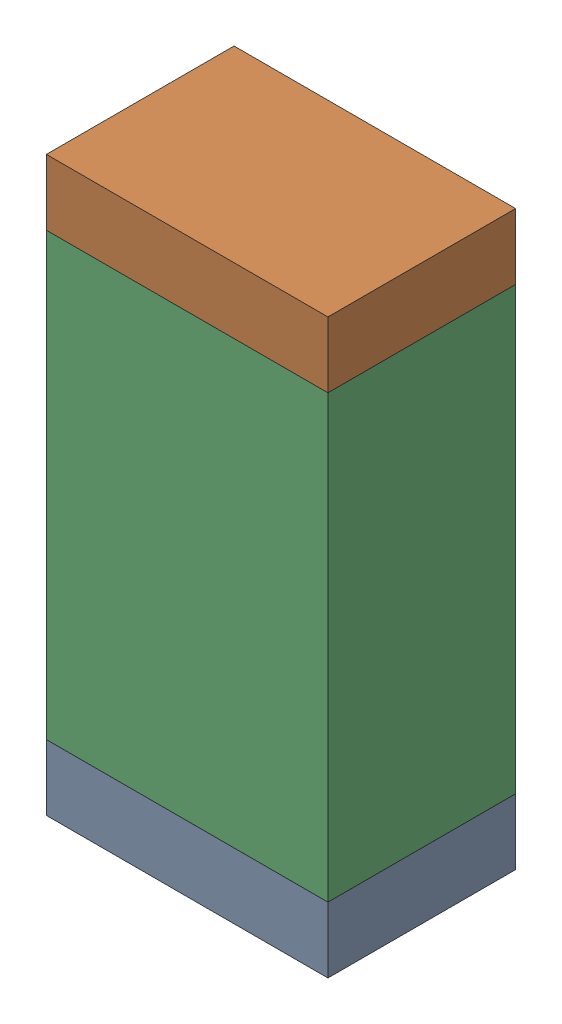
SolidWorks assembly C3, configuration Default. Lengths in mm.
Overall size (0.76 1.55 0.51).
6 component instances, 2 part files, 0 mates.
Components (placement in the parent):
- 822501776-1: 822501776 [Default] at (28.447 8.0951 0) size (0.76 0.18 0.51)
  - Extruded_3-1: Extruded_3 [Default] at origin size (0.76 0.18 0.51)
- 822501776-2: 822501776 [Default] at (28.447 9.4667 0) size (0.76 0.18 0.51)
  - Extruded_3-1: Extruded_3 [Default] at origin size (0.76 0.18 0.51)
- 822501912-1: 822501912 [Default] at (28.447 8.781 0) size (0.76 1.19 0.51)
  - Extruded_4-1: Extruded_4 [Default] at origin size (0.76 1.19 0.51)
